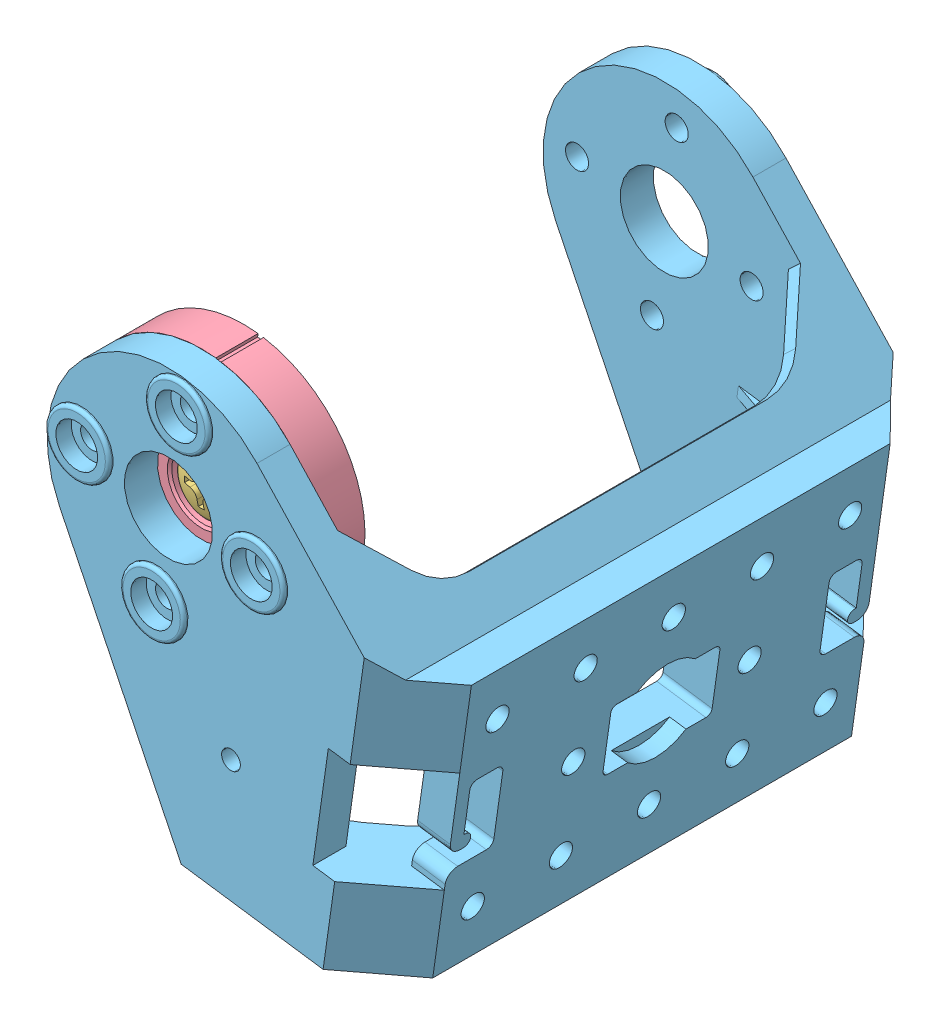
SolidWorks assembly axe roue avec F1, configuration Défaut. Lengths in mm.
Overall size (38.99 42.39 48.8).
6 component instances, 5 part files, 7 mates.
Components (placement in the parent):
- ASSY_GEAR-WHEEL___DUMMY-1: ASSY_GEAR-WHEEL___DUMMY [Défaut] at (0.1197 -0.3305 -1.3436) size (6.5 6.5 5.51)
- BHS_M2_6X8-1: BHS_M2_6X8 [Défaut] at (0.1197 -0.3305 -1.2736) size (5.92 5.92 9.6)
  - BHS_M2_6X8-1: BHS_M2_6X8 [Défaut] at origin size (2.15 2.15 8)
  - BHS_M2_6X8-1-1: BHS_M2_6X8-1 [Défaut] at origin size (5.92 5.92 9.6)
- DC04_B01_HORN2_DUMMY-1: DC04_B01_HORN2_DUMMY [Défaut] at (0.1197 -0.3305 -1.2736) x (0.990114 -0.140262 0) z (0 0 1) size (22 22 6.71)
- F1-1: F1 [Défaut] at (0.1197 -0.3305 -1.4036) x (0 0 1) z (0.990114 -0.140262 0) size (48.8 38 34)
Mates (geometry in assembly coordinates):
- Coaxiale2: concentric: cylinder of ASSY_GEAR-WHEEL___DUMMY-1 through (0.1197 -0.3305 12.5564) axis (0 0 1) radius 2.9; cylinder of DC04_B01_HORN2_DUMMY-1 through (0.1197 -0.3305 16.5564) axis (0 0 -1) radius 2.95
- Coïncidente2: coincident: plane of ASSY_GEAR-WHEEL___DUMMY-1 through (-2.4806 -2.93 16.5564) normal (0 0 1); plane of DC04_B01_HORN2_DUMMY-1 through (-2.4877 3.1375 16.5564) normal (0 0 -1)
- Coaxiale3: concentric: cylinder of BHS_M2_6X8-1/BHS_M2_6X8-1-1 through (0.1197 -0.3305 18.2064) axis (0 0 -1) radius 1.3; cylinder of DC04_B01_HORN2_DUMMY-1 through (0.1197 -0.3305 18.2064) axis (0 0 -1) radius 1.3
- Coïncidente3: coincident: plane of BHS_M2_6X8-1/BHS_M2_6X8-1-1 through (-2.3535 2.1427 18.2064) normal (0 0 -1); plane of DC04_B01_HORN2_DUMMY-1 through (-2.4671 2.926 18.2064) normal (0 0 1)
- Coaxiale4: concentric: cone of DC04_B01_HORN2_DUMMY-1 through (0.1197 -0.3305 15.7564) axis (0 0 -1); cylinder of F1-1 through (0.1197 -0.3305 19.5964) axis (0 0 1) radius 4
- Coïncidente4: coincident: plane of DC04_B01_HORN2_DUMMY-1 through (-9.6058 12.5986 19.5964) normal (0 0 1); plane of F1-1 through (13.3676 -30.2444 19.5964) normal (0 0 -1)
- Coaxiale5: concentric anti-aligned: cylinder of DC04_B01_HORN2_DUMMY-1 through (-7.8012 0.7916 17.7564) axis (0 0 1) radius 1.05; cylinder of F1-1 through (-7.8012 0.7916 21.5964) axis (0 0 -1) radius 1.05
